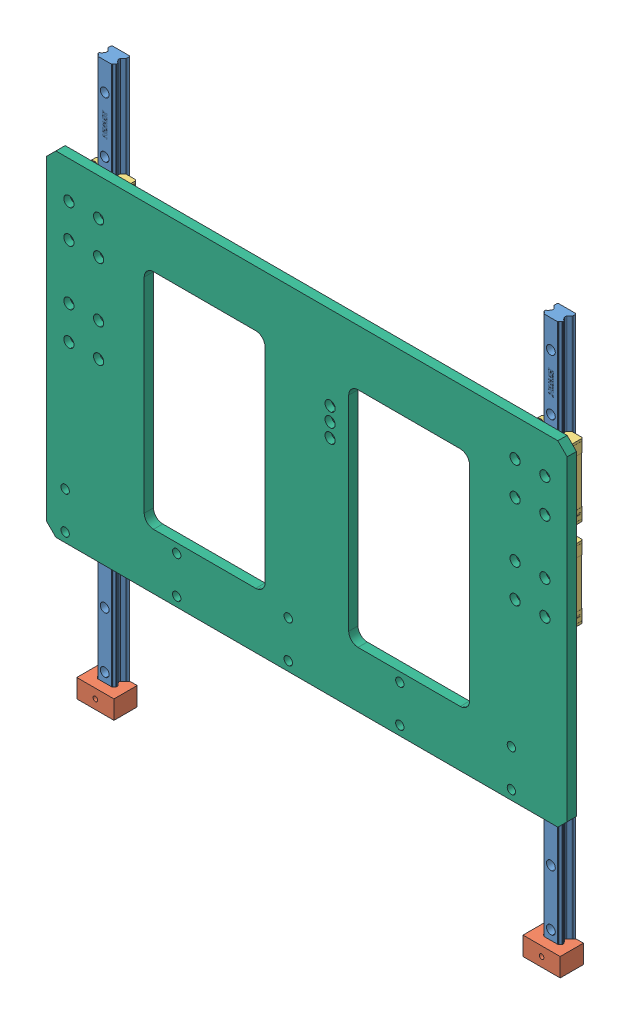
SolidWorks assembly 上下滑轨, configuration 默认. Lengths in mm.
Overall size (560 600 40.65).
21 component instances, 6 part files, 26 mates.
Components (placement in the parent):
- HGR20 导轨-1: HGR20 导轨 [默认] at (-2637.4955 915.981 3304.5173) x (-1 0 0) z (0 1 0) size (20 17.5 600)
- 直线导轨限位块-1: 直线导轨限位块 [默认] at (-2638.0215 365.931 3312.17) x (-1 0 0) z (0 -1 0) size (40 25 20)
- HGR20 滑块-1: HGR20 滑块 [默认] at (-2638.0215 557.681 3314.67) x (0 -1 0) z (-1 0 0) size (97.48 36.05 44)
  - LM滑块-1: LM滑块 [默认] at (-242 0 0) x (0 0 -1) z (1 0 0) size (44 25.4 77.5)
  - 螺纹接头-1: 螺纹接头 [默认] at (-295.1321 19.3089 7.0344) x (-0.46194 0.191342 -0.866025) z (-0.745248 -0.613137 0.262049) size (15.11 19.64 23.4)
  - M6H-1: M6H [默认] at (-205.2216 7.1862 0) x (0 1 0) z (1 0 0) size (8 8 8)
- 高型连接板1-1: 高型连接板1 [默认] at (-2398.0215 677.681 3337.17) x (-1 0 0) z (0 0 -1) size (560 360 10)
- HGR20 滑块-2: HGR20 滑块 [默认] at (-2638.0215 462.681 3314.67) x (0 -1 0) z (-1 0 0) size (97.48 36.05 44)
  - LM滑块-1: LM滑块 [默认] at (-242 0 0) x (0 0 -1) z (1 0 0) size (44 25.4 77.5)
  - 螺纹接头-1: 螺纹接头 [默认] at (-295.1321 19.3089 7.0344) x (-0.46194 0.191342 -0.866025) z (-0.745248 -0.613137 0.262049) size (15.11 19.64 23.4)
  - M6H-1: M6H [默认] at (-205.2216 7.1862 0) x (0 1 0) z (1 0 0) size (8 8 8)
- HGR20 导轨-2: HGR20 导轨 [默认] at (-2157.4955 915.981 3304.5173) x (-1 0 0) z (0 1 0) size (20 17.5 600)
- 直线导轨限位块-2: 直线导轨限位块 [默认] at (-2158.0215 345.931 3312.17) x (1 0 0) z (0 1 0) size (40 25 20)
- HGR20 滑块-6: HGR20 滑块 [默认] at (-2158.0215 557.681 3314.67) x (0 -1 0) z (-1 0 0) size (97.48 36.05 44)
  - LM滑块-1: LM滑块 [默认] at (-242 0 0) x (0 0 -1) z (1 0 0) size (44 25.4 77.5)
  - 螺纹接头-1: 螺纹接头 [默认] at (-295.1321 19.3089 7.0344) x (-0.46194 0.191342 -0.866025) z (-0.745248 -0.613137 0.262049) size (15.11 19.64 23.4)
  - M6H-1: M6H [默认] at (-205.2216 7.1862 0) x (0 1 0) z (1 0 0) size (8 8 8)
- HGR20 滑块-8: HGR20 滑块 [默认] at (-2158.0215 462.681 3314.67) x (0 -1 0) z (-1 0 0) size (97.48 36.05 44)
  - LM滑块-1: LM滑块 [默认] at (-242 0 0) x (0 0 -1) z (1 0 0) size (44 25.4 77.5)
  - 螺纹接头-1: 螺纹接头 [默认] at (-295.1321 19.3089 7.0344) x (-0.46194 0.191342 -0.866025) z (-0.745248 -0.613137 0.262049) size (15.11 19.64 23.4)
  - M6H-1: M6H [默认] at (-205.2216 7.1862 0) x (0 1 0) z (1 0 0) size (8 8 8)
Mates (geometry in assembly coordinates):
- 重合1: coincident aligned: plane of HGR20 导轨-1 through (-2638.0214 345.931 3305.4515) normal (0 -1 0); plane of 直线导轨限位块-1 through (-2638.0215 345.931 3312.17) normal (0 -1 0)
- 重合2: coincident anti-aligned: plane of HGR20 导轨-1 through (-2630.7907 945.931 3314.67) normal (0 0 1); plane of 直线导轨限位块-1 through (-2645.5215 429.9744 3314.67) normal (0 0 -1)
- 重合3: coincident anti-aligned: plane of HGR20 导轨-1 through (-2628.0215 945.931 3310.6363) normal (1 0 0); plane of 直线导轨限位块-1 through (-2628.0215 429.9744 3312.67) normal (-1 0 0)
- 重合4: coincident anti-aligned: plane of HGR20 导轨-1 through (-2630.7907 945.931 3314.67) normal (0 0 1); plane of HGR20 滑块-1/复件 HGH20C_右封_temp-1 through (-2645.2522 824.931 3314.67) normal (0 0 -1)
- 重合5: coincident anti-aligned: plane of HGR20 导轨-1 through (-2628.0215 945.931 3310.6363) normal (1 0 0); plane of HGR20 滑块-1/复件 HGH20C_右封_temp-1 through (-2628.0215 824.931 3311.6936) normal (-1 0 0)
- 同心1: concentric anti-aligned: cylinder of HGR20 滑块-1/复件 HGH20C_右封_temp-1 through (-2654.0215 817.681 3324.17) axis (0 0 1) radius 2.067; circle of 高型连接板1-1
- 同心2: concentric aligned: cylinder of HGR20 滑块-1/复件 HGH20C_右封_temp-1 through (-2622.0215 817.681 3324.17) axis (0 0 1) radius 2.067; cylinder of 高型连接板1-1 through (-2622.0215 817.681 3327.17) axis (0 0 1) radius 3.5
- 重合6: coincident anti-aligned: plane of HGR20 滑块-1/复件 HGH20C_右封_temp-1 through (-2650.0215 824.931 3327.17) normal (0 0 1); plane of 高型连接板1-1 through (-2398.0215 677.681 3327.17) normal (0 0 -1)
- 同心3: concentric anti-aligned: circle of 高型连接板1-1; circle of HGR20 滑块-6/LM滑块-1
- 重合7: coincident anti-aligned: plane of 高型连接板1-1 through (-2398.0215 677.681 3327.17) normal (0 0 -1); plane of HGR20 滑块-6/LM滑块-1 through (-2154.0215 824.931 3327.17) normal (0 0 1)
- 同心4: concentric anti-aligned: circle of 高型连接板1-1; circle of HGR20 滑块-6/LM滑块-1
- LimitDistance1: limit distance = 300 mm anti-aligned: plane of HGR20 滑块-2/LM滑块-1 through (-2638.0446 665.931 3314.495) normal (0 -1 0); plane of 直线导轨限位块-1 through (-2638.0215 365.931 3312.17) normal (0 1 0)
- 重合8: coincident aligned: plane of HGR20 导轨-2 through (-2158.0214 345.931 3305.4515) normal (0 -1 0); plane of 直线导轨限位块-2 through (-2158.0215 345.931 3312.17) normal (0 -1 0)
- 重合9: coincident anti-aligned: plane of HGR20 导轨-2 through (-2150.7907 945.931 3314.67) normal (0 0 1); plane of 直线导轨限位块-2 through (-2150.5215 281.8875 3314.67) normal (0 0 -1)
- 重合10: coincident anti-aligned: plane of HGR20 导轨-2 through (-2168.0215 945.931 3311.6936) normal (-1 0 0); plane of 直线导轨限位块-2 through (-2168.0215 281.8875 3312.67) normal (1 0 0)
- 重合11: coincident anti-aligned: plane of HGR20 导轨-2 through (-2150.7907 945.931 3314.67) normal (0 0 1); plane of HGR20 滑块-6/LM滑块-1 through (-2165.2522 824.931 3314.67) normal (0 0 -1)
- 重合12: coincident anti-aligned: plane of HGR20 导轨-2 through (-2168.0215 945.931 3311.6936) normal (-1 0 0); plane of HGR20 滑块-6/LM滑块-1 through (-2168.0215 824.931 3310.6363) normal (1 0 0)
- 重合13: coincident aligned: plane of HGR20 导轨-1 through (-2638.0214 945.931 3305.4515) normal (0 1 0); plane of HGR20 导轨-2 through (-2158.0214 945.931 3305.4515) normal (0 1 0)
- 重合14: coincident aligned: plane of HGR20 导轨-1 through (-2647.0215 945.931 3297.17) normal (0 0 -1); plane of HGR20 导轨-2 through (-2167.0215 945.931 3297.17) normal (0 0 -1)
- 重合15: coincident aligned: plane of HGR20 导轨-2 through (-2158.0214 345.931 3305.4515) normal (0 -1 0); plane of 直线导轨限位块-2 through (-2158.0215 345.931 3312.17) normal (0 -1 0)
- 同心5: concentric aligned: cylinder of 高型连接板1-1 through (-2622.0215 722.681 3327.17) axis (0 0 1) radius 3.5; cylinder of HGR20 滑块-2/LM滑块-1 through (-2622.0215 722.681 3324.17) axis (0 0 1) radius 2.067
- 同心6: concentric aligned: cylinder of 高型连接板1-1 through (-2654.0215 722.681 3337.17) axis (0 0 1) radius 5.5; cylinder of HGR20 滑块-2/LM滑块-1 through (-2654.0215 722.681 3324.17) axis (0 0 1) radius 2.067
- 重合16: coincident anti-aligned: plane of HGR20 导轨-1 through (-2630.7907 945.931 3314.67) normal (0 0 1); plane of HGR20 滑块-2/LM滑块-1 through (-2645.2522 729.931 3314.67) normal (0 0 -1)
- 重合17: coincident anti-aligned: plane of HGR20 导轨-2 through (-2150.7907 945.931 3314.67) normal (0 0 1); plane of HGR20 滑块-8/LM滑块-1 through (-2165.2522 729.931 3314.67) normal (0 0 -1)
- 同心7: concentric aligned: cylinder of 高型连接板1-1 through (-2174.0215 722.681 3337.17) axis (0 0 1) radius 5.5; cylinder of HGR20 滑块-8/LM滑块-1 through (-2174.0215 722.681 3324.17) axis (0 0 1) radius 2.067
- 同心8: concentric aligned: cylinder of 高型连接板1-1 through (-2142.0215 722.681 3337.17) axis (0 0 1) radius 5.5; cylinder of HGR20 滑块-8/LM滑块-1 through (-2142.0215 722.681 3324.17) axis (0 0 1) radius 2.067
